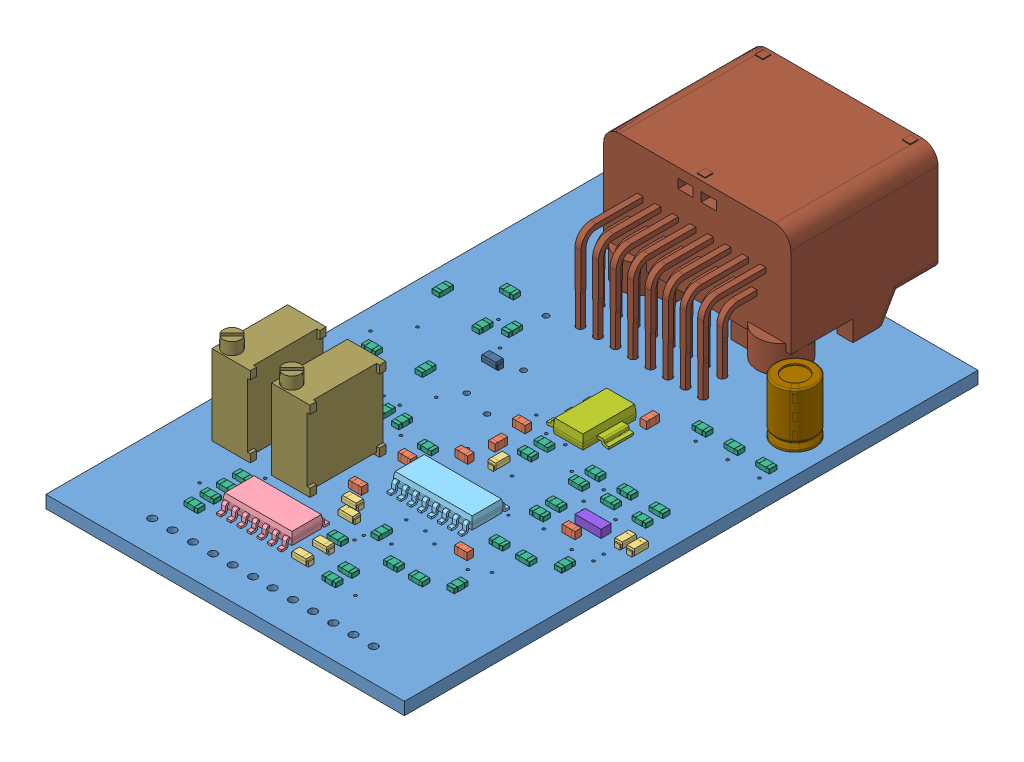
SolidWorks assembly BSPD_RevE, configuration Default. Lengths in mm.
Overall size (45 21.17 78.04).
69 component instances, 13 part files, 16 mates.
Components (placement in the parent):
- PCB Component-1: PCB Component [Default] at (0 0 36) x (1 0 0) z (0 1 0) size (45 72 10.01)
  - Board-1: Board [Default] at origin size (45 72 1.57)
  - 0.1uF-1: 0.1uF [Default] at (19.12 20.08 1.57) size (1.6 0.8 0.9)
  - 0.1uF-2: 0.1uF [Default] at (22.41 30.13 1.57) size (1.6 0.8 0.9)
  - 0.1uF-3: 0.1uF [Default] at (32.85 19.61 1.57) size (1.6 0.8 0.9)
  - 0.1uF-4: 0.1uF [Default] at (37.34 28.66 1.57) size (1.6 0.8 0.9)
  - 0.1uF-5: 0.1uF [Default] at (23.2 33.56 1.57) x (0 1 0) z (0 0 1) size (1.6 0.8 0.9)
  - 0.1uF-6: 0.1uF [Default] at (13.38 27.46 1.57) x (-1 0 0) z (0 0 1) size (1.6 0.8 0.9)
  - 0.1uF-7: 0.1uF [Default] at (30.272 45.517 1.57) x (0 -1 0) z (0 0 1) size (1.6 0.8 0.9)
  - 0.1uF-8: 0.1uF [Default] at (22.705 37.049 1.57) x (-1 0 0) z (0 0 1) size (1.6 0.8 0.9)
  - 0.1uF-9: 0.1uF [Default] at (9.65 27.45 1.57) size (1.6 0.8 0.9)
  - 0.1uF-10: 0.1uF [Default] at (19.189 26.188 1.57) x (-1 0 0) z (0 0 1) size (1.6 0.8 0.9)
  - CDBU0340-HFCDBU0340-HF-1: CDBU0340-HFCDBU0340-HF [Default] at (20.4 18.11 1.57) size (2.1 1 0.85)
  - CDBU0340-HFCDBU0340-HF-2: CDBU0340-HFCDBU0340-HF [Default] at (21.66 16.42 1.57) size (2.1 1 0.85)
  - CDBU0340-HFCDBU0340-HF-3: CDBU0340-HFCDBU0340-HF [Default] at (23.34 8.9 1.57) x (-1 0 0) z (0 0 1) size (2.1 1 0.85)
  - CDBU0340-HFCDBU0340-HF-4: CDBU0340-HFCDBU0340-HF [Default] at (23.33 11.5 1.57) x (-1 0 0) z (0 0 1) size (2.1 1 0.85)
  - CDBU0340-HFCDBU0340-HF-5: CDBU0340-HFCDBU0340-HF [Default] at (25.24 31.623 1.57) x (0 1 0) z (0 0 1) size (2.1 1 0.85)
  - CDBU0340-HFCDBU0340-HF-6: CDBU0340-HFCDBU0340-HF [Default] at (41.75 31 1.57) x (0 -1 0) z (0 0 1) size (2.1 1 0.85)
  - CDBU0340-HFCDBU0340-HF-7: CDBU0340-HFCDBU0340-HF [Default] at (43.25 31 1.57) x (0 -1 0) z (0 0 1) size (2.1 1 0.85)
  - LM239-1: LM239 [Default] at (17 11.5 1.57) x (-1 0 0) z (0 0 1) size (8.65 6 1.75)
  - 4043D-1: 4043D [Default] at (26 24.5 1.57) size (9.9 6 1.75)
  - 10k-1: 10k [Default] at (10.777 11.928 1.57) x (-1 0 0) z (0 0 1) size (1.76 0.96 0.56)
  - 10k-2: 10k [Default] at (2.885 46.919 1.57) x (0 1 0) z (0 0 1) size (1.76 0.96 0.56)
  - 10k-3: 10k [Default] at (9.385 45.419 1.57) x (0 1 0) z (0 0 1) size (1.76 0.96 0.56)
  - 10k-4: 10k [Default] at (11.565 46.919 1.57) x (0 -1 0) z (0 0 1) size (1.76 0.96 0.56)
  - 10k-5: 10k [Default] at (26.09 36.47 1.57) size (1.76 0.96 0.56)
  - 10k-6: 10k [Default] at (26.1 34.41 1.57) x (-1 0 0) z (0 0 1) size (1.76 0.96 0.56)
  - 10k-7: 10k [Default] at (33.37 28.65 1.57) size (1.76 0.96 0.56)
  - 10k-8: 10k [Default] at (33.37 30.68 1.57) x (-1 0 0) z (0 0 1) size (1.76 0.96 0.56)
  - 10k-9: 10k [Default] at (40.5 24.64 1.57) x (0 1 0) z (0 0 1) size (1.76 0.96 0.56)
  - 10k-10: 10k [Default] at (37.36 22.93 1.57) size (1.76 0.96 0.56)
  - 10k-11: 10k [Default] at (10.777 13.978 1.57) size (1.76 0.96 0.56)
  - 10k-12: 10k [Default] at (34 22.93 1.57) x (-1 0 0) z (0 0 1) size (1.76 0.96 0.56)
  - 10k-13: 10k [Default] at (36.5 36.5 1.57) size (1.76 0.96 0.56)
  - 10k-14: 10k [Default] at (32.5 36.5 1.57) size (1.76 0.96 0.56)
  - 10k-15: 10k [Default] at (40.5 36.5 1.57) size (1.76 0.96 0.56)
  - 10k-16: 10k [Default] at (40.5 34.4 1.57) size (1.76 0.96 0.56)
  - 10k-17: 10k [Default] at (32.5 34.4 1.57) size (1.76 0.96 0.56)
  - 10k-18: 10k [Default] at (36.51 34.4 1.57) size (1.76 0.96 0.56)
  - 10k-19: 10k [Default] at (34.367 48.06 1.57) size (1.76 0.96 0.56)
  - 10k-20: 10k [Default] at (38.357 48.06 1.57) size (1.76 0.96 0.56)
  - 10k-21: 10k [Default] at (42.357 48.06 1.57) size (1.76 0.96 0.56)
  - 10k-22: 10k [Default] at (14.686 29.995 1.57) x (0 1 0) z (0 0 1) size (1.76 0.96 0.56)
  - 10k-23: 10k [Default] at (4.819 32.007 1.57) x (-1 0 0) z (0 0 1) size (1.76 0.96 0.56)
  - 10k-24: 10k [Default] at (4.819 34.057 1.57) x (-1 0 0) z (0 0 1) size (1.76 0.96 0.56)
  - 10k-25: 10k [Default] at (4.819 36.097 1.57) size (1.76 0.96 0.56)
  - 10k-26: 10k [Default] at (12.53 30 1.57) x (0 1 0) z (0 0 1) size (1.76 0.96 0.56)
  - 10k-27: 10k [Default] at (7.367 50.899 1.57) x (-1 0 0) z (0 0 1) size (1.76 0.96 0.56)
  - 10k-28: 10k [Default] at (8.28 30.02 1.57) x (0 1 0) z (0 0 1) size (1.76 0.96 0.56)
  - 10k-29: 10k [Default] at (25.5 16.65 1.57) x (0 -1 0) z (0 0 1) size (1.76 0.96 0.56)
  - 10k-30: 10k [Default] at (27.5 10.5 1.57) size (1.76 0.96 0.56)
  - 10k-31: 10k [Default] at (35.99 15.66 1.57) x (0 1 0) z (0 0 1) size (1.76 0.96 0.56)
  - 10k-32: 10k [Default] at (32.85 14 1.57) size (1.76 0.96 0.56)
  - 10k-33: 10k [Default] at (29.68 14 1.57) x (-1 0 0) z (0 0 1) size (1.76 0.96 0.56)
  - 10k-34: 10k [Default] at (10.5 30 1.57) x (0 1 0) z (0 0 1) size (1.76 0.96 0.56)
  - 10k-35: 10k [Default] at (27.506 8.467 1.57) x (-1 0 0) z (0 0 1) size (1.76 0.96 0.56)
  - 10k-36: 10k [Default] at (23.353 13.262 1.57) x (-1 0 0) z (0 0 1) size (1.76 0.96 0.56)
  - 10k-37: 10k [Default] at (10.48 37.174 1.57) x (0 1 0) z (0 0 1) size (1.76 0.96 0.56)
  - 10k-38: 10k [Default] at (10.776 9.896 1.57) x (-1 0 0) z (0 0 1) size (1.76 0.96 0.56)
  - 10k-39: 10k [Default] at (10.784 7.875 1.57) size (1.76 0.96 0.56)
  - 10k-40: 10k [Default] at (19.161 28.784 1.57) x (-1 0 0) z (0 0 1) size (1.76 0.96 0.56)
  - MIC5239-1: MIC5239 [Default] at (27.19 41.706 1.57) x (0 -1 0) z (0 0 1) size (6.7 6.67 1.8)
  - 87758-0216-1: 87758-0216 [Default] at (38 30.68 1.57) x (0 -1 0) z (0 0 1) size (1.27 3.27 1)
  - 47uF-1: 47uF [Default] at (40.87 53.168 1.57) x (0.707107 -0.707107 0) z (0 0 1) size (5 5 10.01)
  - CDBU0340-HF-1: CDBU0340-HF [Default] at (13.888 42.173 1.57) size (2.1 1 0.85)
- K3D-MX34016NF1-V3_JAE_Proprietary-1: K3D-MX34016NF1-V3_JAE_Proprietary [Default] at (22.409 1.57 -41.84) x (-1 0 0) z (0 0 -1) size (23.5 19.2 26.52)
- Trimpot_3296W-1: Trimpot_3296W [Valor predeterminado] at (6.995 1.57 15) x (0 0 1) z (0 1 0) size (9.53 4.83 14.15)
- Trimpot_3296W-2: Trimpot_3296W [Valor predeterminado] at (14.495 1.57 15) x (0 0 1) z (0 1 0) size (9.53 4.83 14.15)
- Part27^BSPD_RevE-1: Part27^BSPD_RevE [Default] at (0 0 36) x (-1 0 0) z (0 -1 0) size (20.7 3.2 3.6) (virtual)
Mates (geometry in assembly coordinates):
- Coincident1: coincident: plane of PCB Component-1/Board-1 through (22.5 0 0) normal (0 -1 0); plane of assembly through (0 0 0) normal (0 1 0)
- Coincident2: coincident: plane of PCB Component-1/Board-1 through (0 0 -36) normal (-1 0 0); plane of assembly through (0 0 0) normal (1 0 0)
- Symmetric1: symmetric: plane of PCB Component-1/Board-1 through (45 0 -36) normal (0 0 -1); plane of PCB Component-1/Board-1 through (0 0 36) normal (0 0 1); plane of assembly
- Concentric3: concentric: circle of PCB Component-1/Board-1; circle of K3D-MX34016NF1-V3_JAE_Proprietary-1
- Concentric4: concentric: circle of PCB Component-1/Board-1; circle of K3D-MX34016NF1-V3_JAE_Proprietary-1
- Coincident4: coincident: plane of PCB Component-1/Board-1 through (22.5 1.57 0) normal (0 1 0); plane of K3D-MX34016NF1-V3_JAE_Proprietary-1 through (12.659 1.57 -31.14) normal (0 -1 0)
- Concentric5: concentric: circle of PCB Component-1/Board-1; circle of Trimpot_3296W-1
- Parallel1: parallel: plane of PCB Component-1/Board-1 through (0 0 -36) normal (-1 0 0); plane of Trimpot_3296W-1 through (4.58 1.57 15) normal (-1 0 0)
- Coincident6: coincident: plane of PCB Component-1/Board-1 through (22.5 1.57 0) normal (0 1 0); plane of Trimpot_3296W-1 through (9.41 1.57 10.235) normal (0 -1 0)
- Concentric6: concentric: circle of PCB Component-1/Board-1; circle of Trimpot_3296W-2
- Parallel2: parallel: plane of PCB Component-1/Board-1 through (0 0 -36) normal (-1 0 0); plane of Trimpot_3296W-2 through (12.08 1.57 15) normal (-1 0 0)
- Coincident8: coincident: plane of PCB Component-1/Board-1 through (22.5 1.57 0) normal (0 1 0); plane of Trimpot_3296W-2 through (16.91 1.57 10.235) normal (0 -1 0)
- InPlace1: in place: plane of PCB Component-1/Board-1 through (22.5 0 0) normal (0 -1 0); plane of ? through (0 0 0) normal (0 -1 0); moOrthogonalPlaneRef_w of PCB Component-1/Board-1 through (22.5 0 0) normal (0 -1 0); plane of ? through (0 0 0) normal (0 0 -1); plane of PCB Component-1/Board-1 through (22.5 0 0) normal (0 -1 0); plane of ? through (0 0 0) normal (-1 0 0); plane of PCB Component-1/Board-1 through (22.5 0 0) normal (0 -1 0); unknown of Part27^BSPD_RevE-1
- Coincident9: coincident: plane of PCB Component-1/Board-1; plane of Part27^BSPD_RevE-1
- Coincident10: coincident: moOrthogonalPlaneRef_w of PCB Component-1/Board-1 through (0 0 36) normal (0 0 -1); plane of Part27^BSPD_RevE-1 through (0 0 36) normal (0 0 -1)
- Coincident11: coincident: moOrthogonalPlaneRef_w of PCB Component-1/Board-1 through (0 0 36) normal (1 0 0); plane of Part27^BSPD_RevE-1 through (0 0 36) normal (-1 0 0)
